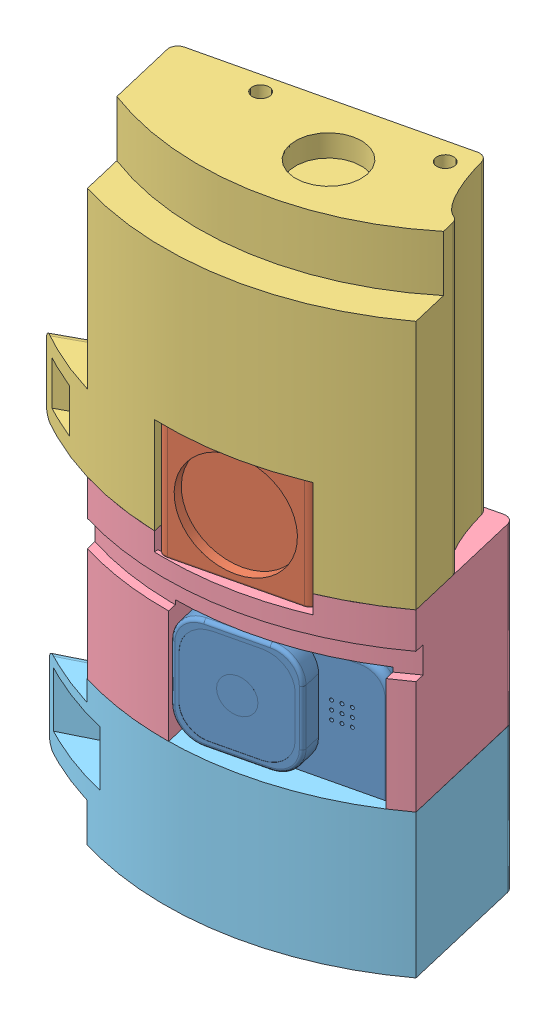
SolidWorks assembly Camera Mount Assembly, configuration Just Mounting. Lengths in mm.
Overall size (112.65 181.05 94.92).
6 component instances, 6 part files, 18 mates.
Components (placement in the parent):
- GoPro Hero 9 by Jon Pardue_fromGrabCad-1: GoPro Hero 9 by Jon Pardue_fromGrabCad [Default] at (-188.2157 -96.1946 17.3774) x (0 1 0) z (0.97328 0 -0.229622) size (72.1 33.6 50.5)
- Nose2BodyCoupler-1: Nose2BodyCoupler [Default] at (-61.1222 -261.2217 -98.0745) x (-0.289671 0 0.957126) z (-0.957126 0 -0.289671) (suppressed, hidden)
- Camera Weight Block-1: Camera Weight Block [Default] at (-188.4379 4.4964 33.0134) x (0.23071 0 0.973023) z (0 1 0) size (35.56 39.37 38.1)
- V2.2 Camera Mount Top-1: V2.2 Camera Mount Top [V2] at (-182.0364 81.6604 -41.5505) x (-0.893546 0 0.448972) z (0.448972 0 0.893546) size (97.25 88.77 57.36)
- V2.2 Camera Mount Middle-1: V2.2 Camera Mount Middle [V2] at (-182.0364 -57.7336 -41.5505) size (88.28 50.8 54.91)
- V2.2 Camera Mount Bottom-1: V2.2 Camera Mount Bottom [V2] at (-182.0364 -99.3896 -41.5505) x (0.999999 0 0.001117) z (-0.001117 0 0.999999) size (100.51 41.66 54.9)
Mates (geometry in assembly coordinates):
- Lock1: lock: unknown of Camera Mount Plate-1; unknown of Nose2BodyCoupler-1
- Distance1: distance = 0.635 mm anti-aligned: plane of Camera Weight Block-1 through (-188.4379 4.4964 33.0134) normal (-0.973023 0 0.23071); plane of V2.2 Camera Mount Top-1 through (-185.2468 23.5464 49.2245) normal (0.973023 0 -0.23071)
- Coincident2: coincident anti-aligned: plane of Camera Weight Block-1 through (-155.4678 23.5464 6.923) normal (0 1 0); plane of V2.2 Camera Mount Top-1 through (-182.0364 23.5464 -41.5505) normal (0 -1 0)
- Coincident3: coincident anti-aligned: plane of Camera Weight Block-1 through (-155.4678 -14.5536 6.923) normal (-0.23071 0 -0.973023); plane of V2.2 Camera Mount Top-1 through (-193.1578 23.5464 15.8595) normal (0.23071 0 0.973023)
- Concentric1: concentric aligned: circle of V2.2 Camera Mount Top-1; circle of V2.2 Camera Mount Middle-1
- Concentric31: concentric aligned: cylinder of Nose2BodyCoupler-1 through (-61.1222 132.4783 -98.0745) axis (0 -1 0) radius 96.6927; cylinder of V2.2 Camera Mount Bottom-1 through (-182.0364 -57.7336 -41.5505) axis (0 -1 0) radius 91.821
- Coincident8: coincident anti-aligned: plane of GoPro Hero 9 by Jon Pardue_fromGrabCad-1 through (-188.2157 -96.2146 17.3774) normal (0 -1 0); plane of V2.2 Camera Mount Bottom-1 through (-182.0364 -96.2146 -41.5505) normal (0 1 0)
- Coincident9: coincident anti-aligned: plane of GoPro Hero 9 by Jon Pardue_fromGrabCad-1 through (-147.82 -87.6946 7.8675) normal (-0.229622 0 -0.97328); plane of V2.2 Camera Mount Bottom-1 through (-185.776 -96.2146 16.8223) normal (0.229622 0 0.97328)
- Coincident10: coincident anti-aligned: plane of GoPro Hero 9 by Jon Pardue_fromGrabCad-1 through (-133.1912 -32.1946 32.8561) normal (0.97328 0 -0.229622); plane of V2.2 Camera Mount Bottom-1 through (-152.3955 -99.3896 -48.5436) normal (-0.97328 0 0.229622)
- Coincident11: coincident aligned: circle of V2.2 Camera Mount Middle-1; circle of V2.2 Camera Mount Bottom-1
- Coincident14: coincident aligned: plane of V2.2 Camera Mount Middle-1; plane of V2.2 Camera Mount Bottom-1
- Parallel1: parallel aligned: plane of V2.2 Camera Mount Top-1 through (-277.331 31.566 18.9732) normal (-0.227889 0 -0.973687); plane of V2.2 Camera Mount Middle-1
- Coincident16: coincident anti-aligned: plane of V2.2 Camera Mount Top-1 through (-182.0364 -6.9336 -41.5505) normal (0 -1 0); plane of V2.2 Camera Mount Middle-1 through (-182.0364 -6.9336 -41.5505) normal (0 1 0)
- Concentric32: concentric anti-aligned: cylinder of V2.2 Camera Mount Top-1 through (-182.0364 -6.9336 -41.5505) axis (0 1 0) radius 91.821; cylinder of V2.2 Camera Mount Middle-1 through (-182.0364 -6.9336 -41.5505) axis (0 -1 0) radius 91.821
- Concentric33: concentric aligned: cylinder of V2.2 Camera Mount Middle-1 through (-182.0364 -6.9336 -41.5505) axis (0 -1 0) radius 91.821; cylinder of V2.2 Camera Mount Bottom-1 through (-182.0364 -57.7336 -41.5505) axis (0 -1 0) radius 91.821
- Coincident17: coincident anti-aligned: plane of V2.2 Camera Mount Middle-1 through (-182.0364 -57.7336 -41.5505) normal (0 -1 0); plane of V2.2 Camera Mount Bottom-1 through (-182.0364 -57.7336 -41.5505) normal (0 1 0)
- Coincident18: coincident aligned: line of V2.2 Camera Mount Top-1 through (-127.2936 -6.9336 32.1673) axis (0 1 0); line of V2.2 Camera Mount Middle-1 through (-127.2936 -57.7336 32.1673) axis (0 1 0)
- Coincident19: coincident aligned: line of V2.2 Camera Mount Middle-1 through (-127.2936 -57.7336 32.1673) axis (0 1 0); line of V2.2 Camera Mount Bottom-1 through (-127.2936 -99.3896 32.1673) axis (0 1 0)
